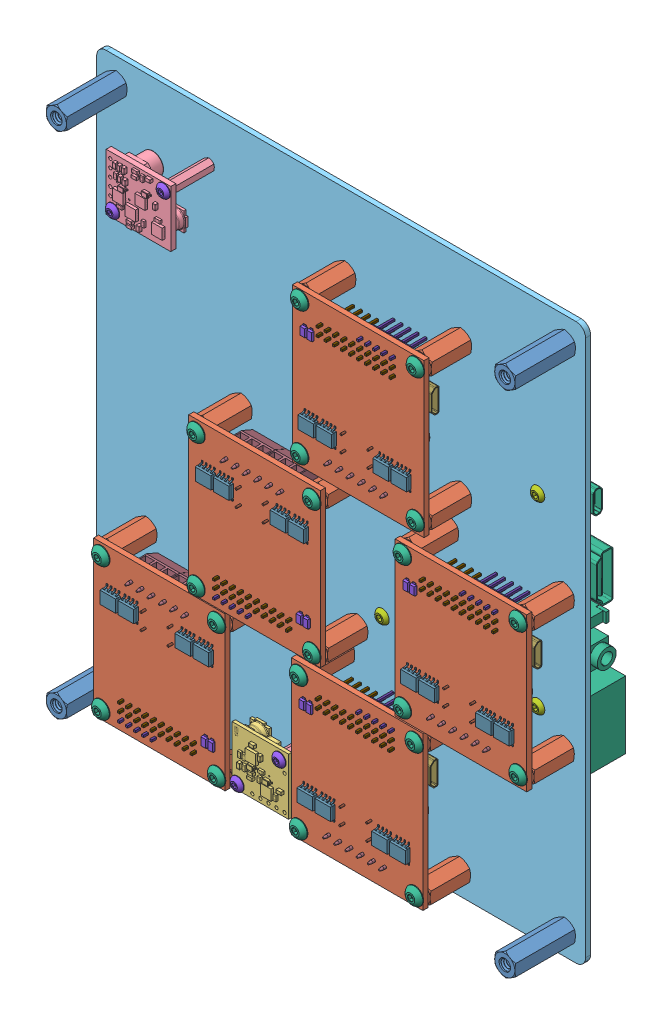
SolidWorks assembly Control Board PCB, configuration Default. Lengths in mm.
Overall size (154 175 47.64).
231 component instances, 26 part files, 69 mates.
Components (placement in the parent):
- 91780A131_ALUM FEM THRDED HEX STANDOFF-1: 91780A131_ALUM FEM THRDED HEX STANDOFF [91780A131] at (-70.612 80.137 11.125) size (6.35 7.33 20.14)
- 91780A164_ALUM FEM THRDED HEX STANDOFF-1: 91780A164_ALUM FEM THRDED HEX STANDOFF [91780A164] at (70.2626 -30.7591 7.95) size (6.35 7.33 13.57)
- 91780A164_ALUM FEM THRDED HEX STANDOFF-2: 91780A164_ALUM FEM THRDED HEX STANDOFF [91780A164] at (5.259 -30.019 7.95) size (6.35 7.33 13.57)
- 91780A164_ALUM FEM THRDED HEX STANDOFF-3: 91780A164_ALUM FEM THRDED HEX STANDOFF [91780A164] at (37.5758 -80.0977 7.95) size (6.35 7.33 13.57)
- 91780A164_ALUM FEM THRDED HEX STANDOFF-4: 91780A164_ALUM FEM THRDED HEX STANDOFF [91780A164] at (-24.7143 -78.6176 7.95) size (6.35 7.33 13.57)
- 91780A164_ALUM FEM THRDED HEX STANDOFF-5: 91780A164_ALUM FEM THRDED HEX STANDOFF [91780A164] at (37.9094 22.4005 7.95) size (6.35 7.33 13.57)
- 95947A005_ALUM FEM THRDED HEX STANDOFF-1: 95947A005_ALUM FEM THRDED HEX STANDOFF [95947A005] at (61.986 34.5817 -5) size (4.5 5.2 10.35)
- 91780A032_ALUM FEM THRDED HEX STANDOFF-1: 91780A032_ALUM FEM THRDED HEX STANDOFF [91780A032] at (-57.5189 59.1317 7.95) size (3.17 3.67 13.32)
- 91780A032_ALUM FEM THRDED HEX STANDOFF-2: 91780A032_ALUM FEM THRDED HEX STANDOFF [91780A032] at (-41.5189 72.6317 7.95) size (3.17 3.67 13.32)
- 91780A032_ALUM FEM THRDED HEX STANDOFF-3: 91780A032_ALUM FEM THRDED HEX STANDOFF [91780A032] at (-18.3018 -77.5283 7.95) size (3.17 3.67 13.32)
- 91780A032_ALUM FEM THRDED HEX STANDOFF-4: 91780A032_ALUM FEM THRDED HEX STANDOFF [91780A032] at (-5.1018 -64.3283 7.95) size (3.17 3.67 13.32)
- Control Board PCB-1: Control Board PCB [Default] at origin size (154 175 1.6)
- 91780A131_ALUM FEM THRDED HEX STANDOFF-2: 91780A131_ALUM FEM THRDED HEX STANDOFF [91780A131] at (-70.612 -80.137 11.125) size (6.35 7.33 20.14)
- 91780A131_ALUM FEM THRDED HEX STANDOFF-3: 91780A131_ALUM FEM THRDED HEX STANDOFF [91780A131] at (70.612 80.137 11.125) size (6.35 7.33 20.14)
- 91780A131_ALUM FEM THRDED HEX STANDOFF-4: 91780A131_ALUM FEM THRDED HEX STANDOFF [91780A131] at (70.612 -80.137 11.125) size (6.35 7.33 20.14)
- 91780A164_ALUM FEM THRDED HEX STANDOFF-6: 91780A164_ALUM FEM THRDED HEX STANDOFF [91780A164] at (70.2626 11.1509 7.95) size (6.35 7.33 13.57)
- 91780A164_ALUM FEM THRDED HEX STANDOFF-7: 91780A164_ALUM FEM THRDED HEX STANDOFF [91780A164] at (33.8136 -30.7591 7.95) size (6.35 7.33 13.57)
- 91780A164_ALUM FEM THRDED HEX STANDOFF-8: 91780A164_ALUM FEM THRDED HEX STANDOFF [91780A164] at (33.8136 11.1509 7.95) size (6.35 7.33 13.57)
- 91780A164_ALUM FEM THRDED HEX STANDOFF-9: 91780A164_ALUM FEM THRDED HEX STANDOFF [91780A164] at (37.9094 64.3105 7.95) size (6.35 7.33 13.57)
- 91780A164_ALUM FEM THRDED HEX STANDOFF-10: 91780A164_ALUM FEM THRDED HEX STANDOFF [91780A164] at (1.4604 22.4005 7.95) size (6.35 7.33 13.57)
- 91780A164_ALUM FEM THRDED HEX STANDOFF-11: 91780A164_ALUM FEM THRDED HEX STANDOFF [91780A164] at (1.4604 64.3105 7.95) size (6.35 7.33 13.57)
- 91780A164_ALUM FEM THRDED HEX STANDOFF-12: 91780A164_ALUM FEM THRDED HEX STANDOFF [91780A164] at (5.259 11.891 7.95) size (6.35 7.33 13.57)
- 91780A164_ALUM FEM THRDED HEX STANDOFF-13: 91780A164_ALUM FEM THRDED HEX STANDOFF [91780A164] at (-31.19 -30.019 7.95) size (6.35 7.33 13.57)
- 91780A164_ALUM FEM THRDED HEX STANDOFF-14: 91780A164_ALUM FEM THRDED HEX STANDOFF [91780A164] at (-31.19 11.891 7.95) size (6.35 7.33 13.57)
- 91780A164_ALUM FEM THRDED HEX STANDOFF-15: 91780A164_ALUM FEM THRDED HEX STANDOFF [91780A164] at (-24.7143 -36.7076 7.95) size (6.35 7.33 13.57)
- 91780A164_ALUM FEM THRDED HEX STANDOFF-16: 91780A164_ALUM FEM THRDED HEX STANDOFF [91780A164] at (-61.1633 -78.6176 7.95) size (6.35 7.33 13.57)
- 91780A164_ALUM FEM THRDED HEX STANDOFF-17: 91780A164_ALUM FEM THRDED HEX STANDOFF [91780A164] at (-61.1633 -36.7076 7.95) size (6.35 7.33 13.57)
- 91780A164_ALUM FEM THRDED HEX STANDOFF-18: 91780A164_ALUM FEM THRDED HEX STANDOFF [91780A164] at (37.5758 -38.1877 7.95) size (6.35 7.33 13.57)
- 91780A164_ALUM FEM THRDED HEX STANDOFF-19: 91780A164_ALUM FEM THRDED HEX STANDOFF [91780A164] at (1.1268 -80.0977 7.95) size (6.35 7.33 13.57)
- 91780A164_ALUM FEM THRDED HEX STANDOFF-20: 91780A164_ALUM FEM THRDED HEX STANDOFF [91780A164] at (1.1268 -38.1877 7.95) size (6.35 7.33 13.57)
- 95947A005_ALUM FEM THRDED HEX STANDOFF-2: 95947A005_ALUM FEM THRDED HEX STANDOFF [95947A005] at (61.986 -23.4183 -5) size (4.5 5.2 10.35)
- 95947A005_ALUM FEM THRDED HEX STANDOFF-3: 95947A005_ALUM FEM THRDED HEX STANDOFF [95947A005] at (12.986 34.5817 -5) size (4.5 5.2 10.35)
- 95947A005_ALUM FEM THRDED HEX STANDOFF-4: 95947A005_ALUM FEM THRDED HEX STANDOFF [95947A005] at (12.986 -23.4183 -5) size (4.5 5.2 10.35)
- RASPBERRY PI 3-1: RASPBERRY PI 3 [Default] at (37.486 -4.4183 -10) x (0 -1 0) z (1 0 0) size (87.3 17.5 58.35)
- Roboclaw-1: Roboclaw [Default] at (78.0237 51.263 53.8455) x (-1 0 0) z (0 -1 0) size (41.97 16.45 48.28)
  - 404-1004-1-ND-4: 404-1004-1-ND [Default] at (73.9119 39.5455 59.9969) size (1.6 0.7 0.8)
  - 404-1004-1-ND-5: 404-1004-1-ND [Default] at (73.9119 39.5455 61.8654) size (1.6 0.7 0.8)
  - 404-1004-1-ND-6: 404-1004-1-ND [Default] at (73.9119 39.5455 63.6743) size (1.6 0.7 0.8)
  - DB2W40200LCT-ND-3: DB2W40200LCT-ND [Default] at (76.3453 37.9455 73.6091) x (0 0 1) z (1 0 0) size (3.5 0.8 1.6)
  - DB2W40200LCT-ND-4: DB2W40200LCT-ND [Default] at (74.2192 37.9455 73.6091) x (0 0 1) z (1 0 0) size (3.5 0.8 1.6)
  - 587-3248-1-ND-3: 587-3248-1-ND [Default] at (102.2216 40.4955 58.909) x (0 0 -1) z (1 0 0) size (1.6 1.9 3.2)
  - 587-3248-1-ND-4: 587-3248-1-ND [Default] at (107.6317 40.4955 65.3191) x (0 0 -1) z (1 0 0) size (1.6 1.9 3.2)
  - SRN5040-220MCT-ND-2: SRN5040-220MCT-ND [Default] at (105.6664 42.9455 62.8284) x (-1 0 0) z (0 0 1) size (2.21 2 2.21)
  - P15369TB-ND-3: P15369TB-ND [Default] at (95.395 39.5455 49.7941) x (-1 0 0) z (0 0 -1) size (8 16 8)
  - 609-4618-1-ND-2: 609-4618-1-ND [Default] at (112.2359 40.9455 71.8547) x (0 0 -1) z (1 0 0) size (7.5 3.05 5)
  - ED2636-ND-3: ED2636-ND [Default] at (85.709 39.5455 41.8431) x (-1 0 0) z (0 0 -1) size (10.5 11.85 7)
  - IRF7351TRPBFCT-ND-5: IRF7351TRPBFCT-ND [Default] at (76.1828 37.6966 49.2664) x (-1 0 0) z (0 0 1) size (5 1.75 6.2)
  - IRF7351TRPBFCT-ND-6: IRF7351TRPBFCT-ND [Default] at (81.9001 37.6966 49.2664) x (-1 0 0) z (0 0 1) size (5 1.75 6.2)
  - IRF7351TRPBFCT-ND-7: IRF7351TRPBFCT-ND [Default] at (99.7733 37.6966 49.2664) x (-1 0 0) z (0 0 1) size (5 1.75 6.2)
  - IRF7351TRPBFCT-ND-8: IRF7351TRPBFCT-ND [Default] at (105.4543 37.6966 49.2664) x (-1 0 0) z (0 0 1) size (5 1.75 6.2)
  - 620-1319-1-ND-3: 620-1319-1-ND [Default] at (106.2731 39.6955 50.308) size (7.8 1.2 6.4)
  - 620-1319-1-ND-4: 620-1319-1-ND [Default] at (77.2465 39.6955 50.308) size (7.8 1.2 6.4)
  - ATXMEGA32A4U-AU-ND-2: ATXMEGA32A4U-AU-ND [Default] at (87.74 39.7455 63.8454) x (0 0 -1) z (1 0 0) size (12 1.2 12)
  - PBC05SAAN-2: PBC05SAAN [Default] at (92.2279 39.5455 80.6492) size (12.7 11.43 2.54)
  - PBC10DAAN-2: PBC10DAAN [Default] at (79.5294 39.5455 76.739) size (25.4 11.43 5.08)
  - SW1020CT-ND-4: SW1020CT-ND [Default] at (73.2925 39.5455 66.2406) x (-1 0 0) z (0 0 -1) size (4 1.6 2.5)
  - SW1020CT-ND-5: SW1020CT-ND [Default] at (73.2925 39.5455 70.7286) x (-1 0 0) z (0 0 -1) size (4 1.6 2.5)
  - SW1020CT-ND-6: SW1020CT-ND [Default] at (73.2925 39.5455 75.1362) x (-1 0 0) z (0 0 -1) size (4 1.6 2.5)
  - P15369TB-ND-4: P15369TB-ND [Default] at (86.9008 39.5455 49.7923) x (-1 0 0) z (0 0 -1) size (8 16 8)
  - ED2636-ND-4: ED2636-ND [Default] at (96.2918 39.5455 41.8431) x (-1 0 0) z (0 0 -1) size (10.5 11.85 7)
  - MC5A-PCB-2: MC5A-PCB [Default] at (90.9892 37.9455 60.0095) size (41.44 1.6 48.28)
- Roboclaw-2: Roboclaw [Default] at (48.0505 2.6645 53.8455) x (-1 0 0) z (0 -1 0) size (41.97 16.45 48.28)
  - 404-1004-1-ND-4: 404-1004-1-ND [Default] at (73.9119 39.5455 59.9969) size (1.6 0.7 0.8)
  - 404-1004-1-ND-5: 404-1004-1-ND [Default] at (73.9119 39.5455 61.8654) size (1.6 0.7 0.8)
  - 404-1004-1-ND-6: 404-1004-1-ND [Default] at (73.9119 39.5455 63.6743) size (1.6 0.7 0.8)
  - DB2W40200LCT-ND-3: DB2W40200LCT-ND [Default] at (76.3453 37.9455 73.6091) x (0 0 1) z (1 0 0) size (3.5 0.8 1.6)
  - DB2W40200LCT-ND-4: DB2W40200LCT-ND [Default] at (74.2192 37.9455 73.6091) x (0 0 1) z (1 0 0) size (3.5 0.8 1.6)
  - 587-3248-1-ND-3: 587-3248-1-ND [Default] at (102.2216 40.4955 58.909) x (0 0 -1) z (1 0 0) size (1.6 1.9 3.2)
  - 587-3248-1-ND-4: 587-3248-1-ND [Default] at (107.6317 40.4955 65.3191) x (0 0 -1) z (1 0 0) size (1.6 1.9 3.2)
  - SRN5040-220MCT-ND-2: SRN5040-220MCT-ND [Default] at (105.6664 42.9455 62.8284) x (-1 0 0) z (0 0 1) size (2.21 2 2.21)
  - P15369TB-ND-3: P15369TB-ND [Default] at (95.395 39.5455 49.7941) x (-1 0 0) z (0 0 -1) size (8 16 8)
  - 609-4618-1-ND-2: 609-4618-1-ND [Default] at (112.2359 40.9455 71.8547) x (0 0 -1) z (1 0 0) size (7.5 3.05 5)
  - ED2636-ND-3: ED2636-ND [Default] at (85.709 39.5455 41.8431) x (-1 0 0) z (0 0 -1) size (10.5 11.85 7)
  - IRF7351TRPBFCT-ND-5: IRF7351TRPBFCT-ND [Default] at (76.1828 37.6966 49.2664) x (-1 0 0) z (0 0 1) size (5 1.75 6.2)
  - IRF7351TRPBFCT-ND-6: IRF7351TRPBFCT-ND [Default] at (81.9001 37.6966 49.2664) x (-1 0 0) z (0 0 1) size (5 1.75 6.2)
  - IRF7351TRPBFCT-ND-7: IRF7351TRPBFCT-ND [Default] at (99.7733 37.6966 49.2664) x (-1 0 0) z (0 0 1) size (5 1.75 6.2)
  - IRF7351TRPBFCT-ND-8: IRF7351TRPBFCT-ND [Default] at (105.4543 37.6966 49.2664) x (-1 0 0) z (0 0 1) size (5 1.75 6.2)
  - 620-1319-1-ND-3: 620-1319-1-ND [Default] at (106.2731 39.6955 50.308) size (7.8 1.2 6.4)
  - 620-1319-1-ND-4: 620-1319-1-ND [Default] at (77.2465 39.6955 50.308) size (7.8 1.2 6.4)
  - ATXMEGA32A4U-AU-ND-2: ATXMEGA32A4U-AU-ND [Default] at (87.74 39.7455 63.8454) x (0 0 -1) z (1 0 0) size (12 1.2 12)
  - PBC05SAAN-2: PBC05SAAN [Default] at (92.2279 39.5455 80.6492) size (12.7 11.43 2.54)
  - PBC10DAAN-2: PBC10DAAN [Default] at (79.5294 39.5455 76.739) size (25.4 11.43 5.08)
  - SW1020CT-ND-4: SW1020CT-ND [Default] at (73.2925 39.5455 66.2406) x (-1 0 0) z (0 0 -1) size (4 1.6 2.5)
  - SW1020CT-ND-5: SW1020CT-ND [Default] at (73.2925 39.5455 70.7286) x (-1 0 0) z (0 0 -1) size (4 1.6 2.5)
  - SW1020CT-ND-6: SW1020CT-ND [Default] at (73.2925 39.5455 75.1362) x (-1 0 0) z (0 0 -1) size (4 1.6 2.5)
  - P15369TB-ND-4: P15369TB-ND [Default] at (86.9008 39.5455 49.7923) x (-1 0 0) z (0 0 -1) size (8 16 8)
  - ED2636-ND-4: ED2636-ND [Default] at (96.2918 39.5455 41.8431) x (-1 0 0) z (0 0 -1) size (10.5 11.85 7)
  - MC5A-PCB-2: MC5A-PCB [Default] at (90.9892 37.9455 60.0095) size (41.44 1.6 48.28)
- Roboclaw-3: Roboclaw [Default] at (-38.9511 -70.1311 53.8455) x (1 0 0) z (0 1 0) size (41.97 16.45 48.28)
  - 404-1004-1-ND-4: 404-1004-1-ND [Default] at (73.9119 39.5455 59.9969) size (1.6 0.7 0.8)
  - 404-1004-1-ND-5: 404-1004-1-ND [Default] at (73.9119 39.5455 61.8654) size (1.6 0.7 0.8)
  - 404-1004-1-ND-6: 404-1004-1-ND [Default] at (73.9119 39.5455 63.6743) size (1.6 0.7 0.8)
  - DB2W40200LCT-ND-3: DB2W40200LCT-ND [Default] at (76.3453 37.9455 73.6091) x (0 0 1) z (1 0 0) size (3.5 0.8 1.6)
  - DB2W40200LCT-ND-4: DB2W40200LCT-ND [Default] at (74.2192 37.9455 73.6091) x (0 0 1) z (1 0 0) size (3.5 0.8 1.6)
  - 587-3248-1-ND-3: 587-3248-1-ND [Default] at (102.2216 40.4955 58.909) x (0 0 -1) z (1 0 0) size (1.6 1.9 3.2)
  - 587-3248-1-ND-4: 587-3248-1-ND [Default] at (107.6317 40.4955 65.3191) x (0 0 -1) z (1 0 0) size (1.6 1.9 3.2)
  - SRN5040-220MCT-ND-2: SRN5040-220MCT-ND [Default] at (105.6664 42.9455 62.8284) x (-1 0 0) z (0 0 1) size (2.21 2 2.21)
  - P15369TB-ND-3: P15369TB-ND [Default] at (95.395 39.5455 49.7941) x (-1 0 0) z (0 0 -1) size (8 16 8)
  - 609-4618-1-ND-2: 609-4618-1-ND [Default] at (112.2359 40.9455 71.8547) x (0 0 -1) z (1 0 0) size (7.5 3.05 5)
  - ED2636-ND-3: ED2636-ND [Default] at (85.709 39.5455 41.8431) x (-1 0 0) z (0 0 -1) size (10.5 11.85 7)
  - IRF7351TRPBFCT-ND-5: IRF7351TRPBFCT-ND [Default] at (76.1828 37.6966 49.2664) x (-1 0 0) z (0 0 1) size (5 1.75 6.2)
  - IRF7351TRPBFCT-ND-6: IRF7351TRPBFCT-ND [Default] at (81.9001 37.6966 49.2664) x (-1 0 0) z (0 0 1) size (5 1.75 6.2)
  - IRF7351TRPBFCT-ND-7: IRF7351TRPBFCT-ND [Default] at (99.7733 37.6966 49.2664) x (-1 0 0) z (0 0 1) size (5 1.75 6.2)
  - IRF7351TRPBFCT-ND-8: IRF7351TRPBFCT-ND [Default] at (105.4543 37.6966 49.2664) x (-1 0 0) z (0 0 1) size (5 1.75 6.2)
  - 620-1319-1-ND-3: 620-1319-1-ND [Default] at (106.2731 39.6955 50.308) size (7.8 1.2 6.4)
  - 620-1319-1-ND-4: 620-1319-1-ND [Default] at (77.2465 39.6955 50.308) size (7.8 1.2 6.4)
  - ATXMEGA32A4U-AU-ND-2: ATXMEGA32A4U-AU-ND [Default] at (87.74 39.7455 63.8454) x (0 0 -1) z (1 0 0) size (12 1.2 12)
  - PBC05SAAN-2: PBC05SAAN [Default] at (92.2279 39.5455 80.6492) size (12.7 11.43 2.54)
  - PBC10DAAN-2: PBC10DAAN [Default] at (79.5294 39.5455 76.739) size (25.4 11.43 5.08)
  - SW1020CT-ND-4: SW1020CT-ND [Default] at (73.2925 39.5455 66.2406) x (-1 0 0) z (0 0 -1) size (4 1.6 2.5)
  - SW1020CT-ND-5: SW1020CT-ND [Default] at (73.2925 39.5455 70.7286) x (-1 0 0) z (0 0 -1) size (4 1.6 2.5)
  - SW1020CT-ND-6: SW1020CT-ND [Default] at (73.2925 39.5455 75.1362) x (-1 0 0) z (0 0 -1) size (4 1.6 2.5)
  - P15369TB-ND-4: P15369TB-ND [Default] at (86.9008 39.5455 49.7923) x (-1 0 0) z (0 0 -1) size (8 16 8)
  - ED2636-ND-4: ED2636-ND [Default] at (96.2918 39.5455 41.8431) x (-1 0 0) z (0 0 -1) size (10.5 11.85 7)
  - MC5A-PCB-2: MC5A-PCB [Default] at (90.9892 37.9455 60.0095) size (41.44 1.6 48.28)
- Roboclaw-4: Roboclaw [Default] at (-71.3044 -16.9716 53.8455) x (1 0 0) z (0 1 0) size (41.97 16.45 48.28)
  - 404-1004-1-ND-4: 404-1004-1-ND [Default] at (73.9119 39.5455 59.9969) size (1.6 0.7 0.8)
  - 404-1004-1-ND-5: 404-1004-1-ND [Default] at (73.9119 39.5455 61.8654) size (1.6 0.7 0.8)
  - 404-1004-1-ND-6: 404-1004-1-ND [Default] at (73.9119 39.5455 63.6743) size (1.6 0.7 0.8)
  - DB2W40200LCT-ND-3: DB2W40200LCT-ND [Default] at (76.3453 37.9455 73.6091) x (0 0 1) z (1 0 0) size (3.5 0.8 1.6)
  - DB2W40200LCT-ND-4: DB2W40200LCT-ND [Default] at (74.2192 37.9455 73.6091) x (0 0 1) z (1 0 0) size (3.5 0.8 1.6)
  - 587-3248-1-ND-3: 587-3248-1-ND [Default] at (102.2216 40.4955 58.909) x (0 0 -1) z (1 0 0) size (1.6 1.9 3.2)
  - 587-3248-1-ND-4: 587-3248-1-ND [Default] at (107.6317 40.4955 65.3191) x (0 0 -1) z (1 0 0) size (1.6 1.9 3.2)
  - SRN5040-220MCT-ND-2: SRN5040-220MCT-ND [Default] at (105.6664 42.9455 62.8284) x (-1 0 0) z (0 0 1) size (2.21 2 2.21)
  - P15369TB-ND-3: P15369TB-ND [Default] at (95.395 39.5455 49.7941) x (-1 0 0) z (0 0 -1) size (8 16 8)
  - 609-4618-1-ND-2: 609-4618-1-ND [Default] at (112.2359 40.9455 71.8547) x (0 0 -1) z (1 0 0) size (7.5 3.05 5)
  - ED2636-ND-3: ED2636-ND [Default] at (85.709 39.5455 41.8431) x (-1 0 0) z (0 0 -1) size (10.5 11.85 7)
  - IRF7351TRPBFCT-ND-5: IRF7351TRPBFCT-ND [Default] at (76.1828 37.6966 49.2664) x (-1 0 0) z (0 0 1) size (5 1.75 6.2)
  - IRF7351TRPBFCT-ND-6: IRF7351TRPBFCT-ND [Default] at (81.9001 37.6966 49.2664) x (-1 0 0) z (0 0 1) size (5 1.75 6.2)
  - IRF7351TRPBFCT-ND-7: IRF7351TRPBFCT-ND [Default] at (99.7733 37.6966 49.2664) x (-1 0 0) z (0 0 1) size (5 1.75 6.2)
  - IRF7351TRPBFCT-ND-8: IRF7351TRPBFCT-ND [Default] at (105.4543 37.6966 49.2664) x (-1 0 0) z (0 0 1) size (5 1.75 6.2)
  - 620-1319-1-ND-3: 620-1319-1-ND [Default] at (106.2731 39.6955 50.308) size (7.8 1.2 6.4)
  - 620-1319-1-ND-4: 620-1319-1-ND [Default] at (77.2465 39.6955 50.308) size (7.8 1.2 6.4)
  - ATXMEGA32A4U-AU-ND-2: ATXMEGA32A4U-AU-ND [Default] at (87.74 39.7455 63.8454) x (0 0 -1) z (1 0 0) size (12 1.2 12)
  - PBC05SAAN-2: PBC05SAAN [Default] at (92.2279 39.5455 80.6492) size (12.7 11.43 2.54)
  - PBC10DAAN-2: PBC10DAAN [Default] at (79.5294 39.5455 76.739) size (25.4 11.43 5.08)
  - SW1020CT-ND-4: SW1020CT-ND [Default] at (73.2925 39.5455 66.2406) x (-1 0 0) z (0 0 -1) size (4 1.6 2.5)
  - SW1020CT-ND-5: SW1020CT-ND [Default] at (73.2925 39.5455 70.7286) x (-1 0 0) z (0 0 -1) size (4 1.6 2.5)
  - SW1020CT-ND-6: SW1020CT-ND [Default] at (73.2925 39.5455 75.1362) x (-1 0 0) z (0 0 -1) size (4 1.6 2.5)
  - P15369TB-ND-4: P15369TB-ND [Default] at (86.9008 39.5455 49.7923) x (-1 0 0) z (0 0 -1) size (8 16 8)
  - ED2636-ND-4: ED2636-ND [Default] at (96.2918 39.5455 41.8431) x (-1 0 0) z (0 0 -1) size (10.5 11.85 7)
  - MC5A-PCB-2: MC5A-PCB [Default] at (90.9892 37.9455 60.0095) size (41.44 1.6 48.28)
- Roboclaw-5: Roboclaw [Default] at (-71.638 -118.8347 53.8455) x (1 0 0) z (0 1 0) size (41.97 16.45 48.28)
  - 404-1004-1-ND-4: 404-1004-1-ND [Default] at (73.9119 39.5455 59.9969) size (1.6 0.7 0.8)
  - 404-1004-1-ND-5: 404-1004-1-ND [Default] at (73.9119 39.5455 61.8654) size (1.6 0.7 0.8)
  - 404-1004-1-ND-6: 404-1004-1-ND [Default] at (73.9119 39.5455 63.6743) size (1.6 0.7 0.8)
  - DB2W40200LCT-ND-3: DB2W40200LCT-ND [Default] at (76.3453 37.9455 73.6091) x (0 0 1) z (1 0 0) size (3.5 0.8 1.6)
  - DB2W40200LCT-ND-4: DB2W40200LCT-ND [Default] at (74.2192 37.9455 73.6091) x (0 0 1) z (1 0 0) size (3.5 0.8 1.6)
  - 587-3248-1-ND-3: 587-3248-1-ND [Default] at (102.2216 40.4955 58.909) x (0 0 -1) z (1 0 0) size (1.6 1.9 3.2)
  - 587-3248-1-ND-4: 587-3248-1-ND [Default] at (107.6317 40.4955 65.3191) x (0 0 -1) z (1 0 0) size (1.6 1.9 3.2)
  - SRN5040-220MCT-ND-2: SRN5040-220MCT-ND [Default] at (105.6664 42.9455 62.8284) x (-1 0 0) z (0 0 1) size (2.21 2 2.21)
  - P15369TB-ND-3: P15369TB-ND [Default] at (95.395 39.5455 49.7941) x (-1 0 0) z (0 0 -1) size (8 16 8)
  - 609-4618-1-ND-2: 609-4618-1-ND [Default] at (112.2359 40.9455 71.8547) x (0 0 -1) z (1 0 0) size (7.5 3.05 5)
  - ED2636-ND-3: ED2636-ND [Default] at (85.709 39.5455 41.8431) x (-1 0 0) z (0 0 -1) size (10.5 11.85 7)
  - IRF7351TRPBFCT-ND-5: IRF7351TRPBFCT-ND [Default] at (76.1828 37.6966 49.2664) x (-1 0 0) z (0 0 1) size (5 1.75 6.2)
  - IRF7351TRPBFCT-ND-6: IRF7351TRPBFCT-ND [Default] at (81.9001 37.6966 49.2664) x (-1 0 0) z (0 0 1) size (5 1.75 6.2)
  - IRF7351TRPBFCT-ND-7: IRF7351TRPBFCT-ND [Default] at (99.7733 37.6966 49.2664) x (-1 0 0) z (0 0 1) size (5 1.75 6.2)
  - IRF7351TRPBFCT-ND-8: IRF7351TRPBFCT-ND [Default] at (105.4543 37.6966 49.2664) x (-1 0 0) z (0 0 1) size (5 1.75 6.2)
  - 620-1319-1-ND-3: 620-1319-1-ND [Default] at (106.2731 39.6955 50.308) size (7.8 1.2 6.4)
  - 620-1319-1-ND-4: 620-1319-1-ND [Default] at (77.2465 39.6955 50.308) size (7.8 1.2 6.4)
  - ATXMEGA32A4U-AU-ND-2: ATXMEGA32A4U-AU-ND [Default] at (87.74 39.7455 63.8454) x (0 0 -1) z (1 0 0) size (12 1.2 12)
  - PBC05SAAN-2: PBC05SAAN [Default] at (92.2279 39.5455 80.6492) size (12.7 11.43 2.54)
  - PBC10DAAN-2: PBC10DAAN [Default] at (79.5294 39.5455 76.739) size (25.4 11.43 5.08)
  - SW1020CT-ND-4: SW1020CT-ND [Default] at (73.2925 39.5455 66.2406) x (-1 0 0) z (0 0 -1) size (4 1.6 2.5)
  - SW1020CT-ND-5: SW1020CT-ND [Default] at (73.2925 39.5455 70.7286) x (-1 0 0) z (0 0 -1) size (4 1.6 2.5)
  - SW1020CT-ND-6: SW1020CT-ND [Default] at (73.2925 39.5455 75.1362) x (-1 0 0) z (0 0 -1) size (4 1.6 2.5)
  - P15369TB-ND-4: P15369TB-ND [Default] at (86.9008 39.5455 49.7923) x (-1 0 0) z (0 0 -1) size (8 16 8)
  - ED2636-ND-4: ED2636-ND [Default] at (96.2918 39.5455 41.8431) x (-1 0 0) z (0 0 -1) size (10.5 11.85 7)
  - MC5A-PCB-2: MC5A-PCB [Default] at (90.9892 37.9455 60.0095) size (41.44 1.6 48.28)
- d24v22fx-step-down-voltage-regulator-1: d24v22fx-step-down-voltage-regulator [Default] at (-2.8158 -79.8223 15.316) x (-1 0 0) z (0 0 -1) size (17.78 17.78 8.22)
- d24v50f5-step-down-voltage-regulator-1: d24v50f5-step-down-voltage-regulator [Default] at (-59.6799 57.0107 15.8748) x (0 1 0) z (0 0 -1) size (17.78 20.32 8.78)
- 92949A146_18-8 SS BUTTON-HEAD SOCKET CAP SCREW-1: 92949A146_18-8 SS BUTTON-HEAD SOCKET CAP SCREW [92949A146] at (-70.612 80.137 -1.8542) x (-0.923728 -0.383049 0) z (0 0 -1) size (6.65 6.65 11.77)
- 92949A106_18-8 SS BUTTON-HEAD SOCKET CAP SCREW-1: 92949A106_18-8 SS BUTTON-HEAD SOCKET CAP SCREW [92949A106] at (70.2626 -30.7591 -1.4986) x (-0.923728 -0.383049 0) z (0 0 -1) size (5.41 5.41 8.16)
- 92949A106_18-8 SS BUTTON-HEAD SOCKET CAP SCREW-2: 92949A106_18-8 SS BUTTON-HEAD SOCKET CAP SCREW [92949A106] at (-24.7143 -78.6176 -1.4986) x (-0.923728 -0.383049 0) z (0 0 -1) size (5.41 5.41 8.16)
- 92949A106_18-8 SS BUTTON-HEAD SOCKET CAP SCREW-3: 92949A106_18-8 SS BUTTON-HEAD SOCKET CAP SCREW [92949A106] at (5.259 -30.019 -1.4986) x (0.923728 0.383049 0) z (0 0 -1) size (5.41 5.41 8.16)
- 92949A106_18-8 SS BUTTON-HEAD SOCKET CAP SCREW-4: 92949A106_18-8 SS BUTTON-HEAD SOCKET CAP SCREW [92949A106] at (37.9094 22.4005 -1.4986) x (-0.923728 -0.383049 0) z (0 0 -1) size (5.41 5.41 8.16)
- 92949A106_18-8 SS BUTTON-HEAD SOCKET CAP SCREW-5: 92949A106_18-8 SS BUTTON-HEAD SOCKET CAP SCREW [92949A106] at (37.5758 -80.0977 -1.4986) x (-0.923728 -0.383049 0) z (0 0 -1) size (5.41 5.41 8.16)
- 92095A458_18-8 SS BUTTON-HEAD SOCKET CAP SCREW-1: 92095A458_18-8 SS BUTTON-HEAD SOCKET CAP SCREW [92095A458] at (61.986 34.5817 -12.65) x (-0.923728 -0.383049 0) z (0 0 -1) size (4.5 4.5 7.75)
- 91255A077_ALLOY STEEL BUTTON-HEAD SOCKET CAP SCREW-1: 91255A077_ALLOY STEEL BUTTON-HEAD SOCKET CAP SCREW [91255A077] at (-41.5189 72.6317 -1.1684) x (0.923728 0.383049 0) z (0 0 -1) size (4.17 4.17 7.76)
- 91255A077_ALLOY STEEL BUTTON-HEAD SOCKET CAP SCREW-2: 91255A077_ALLOY STEEL BUTTON-HEAD SOCKET CAP SCREW [91255A077] at (-57.5189 59.1317 -1.1684) x (-0.923728 -0.383049 0) z (0 0 -1) size (4.17 4.17 7.76)
- 91255A077_ALLOY STEEL BUTTON-HEAD SOCKET CAP SCREW-3: 91255A077_ALLOY STEEL BUTTON-HEAD SOCKET CAP SCREW [91255A077] at (-5.1018 -64.3283 -1.1684) x (0.923728 0.383049 0) z (0 0 -1) size (4.17 4.17 7.76)
- 91255A077_ALLOY STEEL BUTTON-HEAD SOCKET CAP SCREW-4: 91255A077_ALLOY STEEL BUTTON-HEAD SOCKET CAP SCREW [91255A077] at (-18.3018 -77.5283 -1.1684) x (0.923728 0.383049 0) z (0 0 -1) size (4.17 4.17 7.76)
- 92949A146_18-8 SS BUTTON-HEAD SOCKET CAP SCREW-2: 92949A146_18-8 SS BUTTON-HEAD SOCKET CAP SCREW [92949A146] at (-70.612 -80.137 -1.8542) x (-0.923728 -0.383049 0) z (0 0 -1) size (6.65 6.65 11.77)
- 92949A146_18-8 SS BUTTON-HEAD SOCKET CAP SCREW-3: 92949A146_18-8 SS BUTTON-HEAD SOCKET CAP SCREW [92949A146] at (70.612 80.137 -1.8542) x (-0.923728 -0.383049 0) z (0 0 -1) size (6.65 6.65 11.77)
- 92949A146_18-8 SS BUTTON-HEAD SOCKET CAP SCREW-4: 92949A146_18-8 SS BUTTON-HEAD SOCKET CAP SCREW [92949A146] at (70.612 -80.137 -1.8542) x (-0.923728 -0.383049 0) z (0 0 -1) size (6.65 6.65 11.77)
- 92949A106_18-8 SS BUTTON-HEAD SOCKET CAP SCREW-6: 92949A106_18-8 SS BUTTON-HEAD SOCKET CAP SCREW [92949A106] at (37.9094 64.3105 -1.4986) x (-0.923728 -0.383049 0) z (0 0 -1) size (5.41 5.41 8.16)
- 92949A106_18-8 SS BUTTON-HEAD SOCKET CAP SCREW-7: 92949A106_18-8 SS BUTTON-HEAD SOCKET CAP SCREW [92949A106] at (1.4604 22.4005 -1.4986) x (-0.923728 -0.383049 0) z (0 0 -1) size (5.41 5.41 8.16)
- 92949A106_18-8 SS BUTTON-HEAD SOCKET CAP SCREW-8: 92949A106_18-8 SS BUTTON-HEAD SOCKET CAP SCREW [92949A106] at (1.4604 64.3105 -1.4986) x (-0.923728 -0.383049 0) z (0 0 -1) size (5.41 5.41 8.16)
- 92949A106_18-8 SS BUTTON-HEAD SOCKET CAP SCREW-9: 92949A106_18-8 SS BUTTON-HEAD SOCKET CAP SCREW [92949A106] at (5.259 11.891 -1.4986) x (0.923728 0.383049 0) z (0 0 -1) size (5.41 5.41 8.16)
- 92949A106_18-8 SS BUTTON-HEAD SOCKET CAP SCREW-10: 92949A106_18-8 SS BUTTON-HEAD SOCKET CAP SCREW [92949A106] at (-31.19 -30.019 -1.4986) x (0.923728 0.383049 0) z (0 0 -1) size (5.41 5.41 8.16)
- 92949A106_18-8 SS BUTTON-HEAD SOCKET CAP SCREW-11: 92949A106_18-8 SS BUTTON-HEAD SOCKET CAP SCREW [92949A106] at (-31.19 11.891 -1.4986) x (0.923728 0.383049 0) z (0 0 -1) size (5.41 5.41 8.16)
- 92949A106_18-8 SS BUTTON-HEAD SOCKET CAP SCREW-12: 92949A106_18-8 SS BUTTON-HEAD SOCKET CAP SCREW [92949A106] at (-24.7143 -36.7076 -1.4986) x (-0.923728 -0.383049 0) z (0 0 -1) size (5.41 5.41 8.16)
- 92949A106_18-8 SS BUTTON-HEAD SOCKET CAP SCREW-13: 92949A106_18-8 SS BUTTON-HEAD SOCKET CAP SCREW [92949A106] at (-61.1633 -78.6176 -1.4986) x (-0.923728 -0.383049 0) z (0 0 -1) size (5.41 5.41 8.16)
- 92949A106_18-8 SS BUTTON-HEAD SOCKET CAP SCREW-14: 92949A106_18-8 SS BUTTON-HEAD SOCKET CAP SCREW [92949A106] at (-61.1633 -36.7076 -1.4986) x (-0.923728 -0.383049 0) z (0 0 -1) size (5.41 5.41 8.16)
- 92949A106_18-8 SS BUTTON-HEAD SOCKET CAP SCREW-15: 92949A106_18-8 SS BUTTON-HEAD SOCKET CAP SCREW [92949A106] at (37.5758 -38.1877 -1.4986) x (-0.923728 -0.383049 0) z (0 0 -1) size (5.41 5.41 8.16)
- 92949A106_18-8 SS BUTTON-HEAD SOCKET CAP SCREW-16: 92949A106_18-8 SS BUTTON-HEAD SOCKET CAP SCREW [92949A106] at (1.1268 -80.0977 -1.4986) x (-0.923728 -0.383049 0) z (0 0 -1) size (5.41 5.41 8.16)
- 92949A106_18-8 SS BUTTON-HEAD SOCKET CAP SCREW-17: 92949A106_18-8 SS BUTTON-HEAD SOCKET CAP SCREW [92949A106] at (1.1268 -38.1877 -1.4986) x (-0.923728 -0.383049 0) z (0 0 -1) size (5.41 5.41 8.16)
- 92949A106_18-8 SS BUTTON-HEAD SOCKET CAP SCREW-18: 92949A106_18-8 SS BUTTON-HEAD SOCKET CAP SCREW [92949A106] at (70.2626 11.1509 -1.4986) x (-0.923728 -0.383049 0) z (0 0 -1) size (5.41 5.41 8.16)
- 92949A106_18-8 SS BUTTON-HEAD SOCKET CAP SCREW-19: 92949A106_18-8 SS BUTTON-HEAD SOCKET CAP SCREW [92949A106] at (33.8136 -30.7591 -1.4986) x (-0.923728 -0.383049 0) z (0 0 -1) size (5.41 5.41 8.16)
- 92949A106_18-8 SS BUTTON-HEAD SOCKET CAP SCREW-20: 92949A106_18-8 SS BUTTON-HEAD SOCKET CAP SCREW [92949A106] at (33.8136 11.1509 -1.4986) x (-0.923728 -0.383049 0) z (0 0 -1) size (5.41 5.41 8.16)
- 92095A458_18-8 SS BUTTON-HEAD SOCKET CAP SCREW-3: 92095A458_18-8 SS BUTTON-HEAD SOCKET CAP SCREW [92095A458] at (61.986 -23.4183 -12.65) x (-0.923728 -0.383049 0) z (0 0 -1) size (4.5 4.5 7.75)
- 92095A458_18-8 SS BUTTON-HEAD SOCKET CAP SCREW-4: 92095A458_18-8 SS BUTTON-HEAD SOCKET CAP SCREW [92095A458] at (12.986 34.5817 -12.65) x (-0.923728 -0.383049 0) z (0 0 -1) size (4.5 4.5 7.75)
- 92095A458_18-8 SS BUTTON-HEAD SOCKET CAP SCREW-5: 92095A458_18-8 SS BUTTON-HEAD SOCKET CAP SCREW [92095A458] at (12.986 -23.4183 -12.65) x (-0.923728 -0.383049 0) z (0 0 -1) size (4.5 4.5 7.75)
- 92949A106_18-8 SS BUTTON-HEAD SOCKET CAP SCREW-21: 92949A106_18-8 SS BUTTON-HEAD SOCKET CAP SCREW [92949A106] at (37.9094 64.3105 17.3986) x (0.923728 0.383049 0) z (0 0 1) size (5.41 5.41 8.16)
- 92949A106_18-8 SS BUTTON-HEAD SOCKET CAP SCREW-22: 92949A106_18-8 SS BUTTON-HEAD SOCKET CAP SCREW [92949A106] at (1.4604 22.4005 17.3986) x (0.923728 0.383049 0) z (0 0 1) size (5.41 5.41 8.16)
- 92949A106_18-8 SS BUTTON-HEAD SOCKET CAP SCREW-23: 92949A106_18-8 SS BUTTON-HEAD SOCKET CAP SCREW [92949A106] at (1.4604 64.3105 17.3986) x (0.923728 0.383049 0) z (0 0 1) size (5.41 5.41 8.16)
- 92949A106_18-8 SS BUTTON-HEAD SOCKET CAP SCREW-24: 92949A106_18-8 SS BUTTON-HEAD SOCKET CAP SCREW [92949A106] at (5.259 11.891 17.3986) x (-0.923728 -0.383049 0) z (0 0 1) size (5.41 5.41 8.16)
- 92949A106_18-8 SS BUTTON-HEAD SOCKET CAP SCREW-25: 92949A106_18-8 SS BUTTON-HEAD SOCKET CAP SCREW [92949A106] at (-31.19 -30.019 17.3986) x (-0.923728 -0.383049 0) z (0 0 1) size (5.41 5.41 8.16)
- 92949A106_18-8 SS BUTTON-HEAD SOCKET CAP SCREW-26: 92949A106_18-8 SS BUTTON-HEAD SOCKET CAP SCREW [92949A106] at (-31.19 11.891 17.3986) x (-0.923728 -0.383049 0) z (0 0 1) size (5.41 5.41 8.16)
- 92949A106_18-8 SS BUTTON-HEAD SOCKET CAP SCREW-27: 92949A106_18-8 SS BUTTON-HEAD SOCKET CAP SCREW [92949A106] at (-24.7143 -36.7076 17.3986) x (0.923728 0.383049 0) z (0 0 1) size (5.41 5.41 8.16)
- 92949A106_18-8 SS BUTTON-HEAD SOCKET CAP SCREW-28: 92949A106_18-8 SS BUTTON-HEAD SOCKET CAP SCREW [92949A106] at (-61.1633 -78.6176 17.3986) x (0.923728 0.383049 0) z (0 0 1) size (5.41 5.41 8.16)
- 92949A106_18-8 SS BUTTON-HEAD SOCKET CAP SCREW-29: 92949A106_18-8 SS BUTTON-HEAD SOCKET CAP SCREW [92949A106] at (-61.1633 -36.7076 17.3986) x (0.923728 0.383049 0) z (0 0 1) size (5.41 5.41 8.16)
- 92949A106_18-8 SS BUTTON-HEAD SOCKET CAP SCREW-30: 92949A106_18-8 SS BUTTON-HEAD SOCKET CAP SCREW [92949A106] at (37.5758 -38.1877 17.3986) x (0.923728 0.383049 0) z (0 0 1) size (5.41 5.41 8.16)
- 92949A106_18-8 SS BUTTON-HEAD SOCKET CAP SCREW-31: 92949A106_18-8 SS BUTTON-HEAD SOCKET CAP SCREW [92949A106] at (1.1268 -80.0977 17.3986) x (0.923728 0.383049 0) z (0 0 1) size (5.41 5.41 8.16)
- 92949A106_18-8 SS BUTTON-HEAD SOCKET CAP SCREW-32: 92949A106_18-8 SS BUTTON-HEAD SOCKET CAP SCREW [92949A106] at (1.1268 -38.1877 17.3986) x (0.923728 0.383049 0) z (0 0 1) size (5.41 5.41 8.16)
- 92949A106_18-8 SS BUTTON-HEAD SOCKET CAP SCREW-33: 92949A106_18-8 SS BUTTON-HEAD SOCKET CAP SCREW [92949A106] at (70.2626 11.1509 17.3986) x (0.923728 0.383049 0) z (0 0 1) size (5.41 5.41 8.16)
- 92949A106_18-8 SS BUTTON-HEAD SOCKET CAP SCREW-34: 92949A106_18-8 SS BUTTON-HEAD SOCKET CAP SCREW [92949A106] at (33.8136 -30.7591 17.3986) x (0.923728 0.383049 0) z (0 0 1) size (5.41 5.41 8.16)
- 92949A106_18-8 SS BUTTON-HEAD SOCKET CAP SCREW-35: 92949A106_18-8 SS BUTTON-HEAD SOCKET CAP SCREW [92949A106] at (33.8136 11.1509 17.3986) x (0.923728 0.383049 0) z (0 0 1) size (5.41 5.41 8.16)
- 92949A106_18-8 SS BUTTON-HEAD SOCKET CAP SCREW-36: 92949A106_18-8 SS BUTTON-HEAD SOCKET CAP SCREW [92949A106] at (70.2626 -30.7591 17.3986) x (0.923728 0.383049 0) z (0 0 1) size (5.41 5.41 8.16)
- 92949A106_18-8 SS BUTTON-HEAD SOCKET CAP SCREW-37: 92949A106_18-8 SS BUTTON-HEAD SOCKET CAP SCREW [92949A106] at (-24.7143 -78.6176 17.3986) x (0.923728 0.383049 0) z (0 0 1) size (5.41 5.41 8.16)
- 92949A106_18-8 SS BUTTON-HEAD SOCKET CAP SCREW-38: 92949A106_18-8 SS BUTTON-HEAD SOCKET CAP SCREW [92949A106] at (5.259 -30.019 17.3986) x (-0.923728 -0.383049 0) z (0 0 1) size (5.41 5.41 8.16)
- 92949A106_18-8 SS BUTTON-HEAD SOCKET CAP SCREW-39: 92949A106_18-8 SS BUTTON-HEAD SOCKET CAP SCREW [92949A106] at (37.9094 22.4005 17.3986) x (0.923728 0.383049 0) z (0 0 1) size (5.41 5.41 8.16)
- 92949A106_18-8 SS BUTTON-HEAD SOCKET CAP SCREW-40: 92949A106_18-8 SS BUTTON-HEAD SOCKET CAP SCREW [92949A106] at (37.5758 -80.0977 17.3986) x (0.923728 0.383049 0) z (0 0 1) size (5.41 5.41 8.16)
- 92095A458_18-8 SS BUTTON-HEAD SOCKET CAP SCREW-6: 92095A458_18-8 SS BUTTON-HEAD SOCKET CAP SCREW [92095A458] at (61.986 -23.4183 2.65) x (-0.923728 -0.383049 0) z (0 0 1) size (4.5 4.5 7.75)
- 92095A458_18-8 SS BUTTON-HEAD SOCKET CAP SCREW-7: 92095A458_18-8 SS BUTTON-HEAD SOCKET CAP SCREW [92095A458] at (12.986 34.5817 2.65) x (-0.923728 -0.383049 0) z (0 0 1) size (4.5 4.5 7.75)
- 92095A458_18-8 SS BUTTON-HEAD SOCKET CAP SCREW-8: 92095A458_18-8 SS BUTTON-HEAD SOCKET CAP SCREW [92095A458] at (12.986 -23.4183 2.65) x (-0.923728 -0.383049 0) z (0 0 1) size (4.5 4.5 7.75)
- 92095A458_18-8 SS BUTTON-HEAD SOCKET CAP SCREW-9: 92095A458_18-8 SS BUTTON-HEAD SOCKET CAP SCREW [92095A458] at (61.986 34.5817 2.65) x (-0.923728 -0.383049 0) z (0 0 1) size (4.5 4.5 7.75)
- 91255A077_ALLOY STEEL BUTTON-HEAD SOCKET CAP SCREW-5: 91255A077_ALLOY STEEL BUTTON-HEAD SOCKET CAP SCREW [91255A077] at (-41.5189 72.6317 17.0684) x (0.923728 0.383049 0) z (0 0 1) size (4.17 4.17 7.76)
- 91255A077_ALLOY STEEL BUTTON-HEAD SOCKET CAP SCREW-6: 91255A077_ALLOY STEEL BUTTON-HEAD SOCKET CAP SCREW [91255A077] at (-57.5189 59.1317 17.0684) x (-0.923728 -0.383049 0) z (0 0 1) size (4.17 4.17 7.76)
- 91255A077_ALLOY STEEL BUTTON-HEAD SOCKET CAP SCREW-7: 91255A077_ALLOY STEEL BUTTON-HEAD SOCKET CAP SCREW [91255A077] at (-5.1018 -64.3283 17.0684) x (0.923728 0.383049 0) z (0 0 1) size (4.17 4.17 7.76)
- 91255A077_ALLOY STEEL BUTTON-HEAD SOCKET CAP SCREW-8: 91255A077_ALLOY STEEL BUTTON-HEAD SOCKET CAP SCREW [91255A077] at (-18.3018 -77.5283 17.0684) x (0.923728 0.383049 0) z (0 0 1) size (4.17 4.17 7.76)
Mates (geometry in assembly coordinates):
- Coincident1: coordinate: point of Control Board PCB-1; point of assembly
- Coincident2: coincident anti-aligned: plane of 91780A131_ALUM FEM THRDED HEX STANDOFF-1 through (-70.612 83.8032 1.6) normal (0 0 -1); plane of Control Board PCB-1 through (0 0 1.6) normal (0 0 1)
- Concentric1: concentric anti-aligned: line of 91780A131_ALUM FEM THRDED HEX STANDOFF-1 through (-70.612 80.137 22.4508) axis (0 0 -1); cylinder of Control Board PCB-1 through (-70.612 80.137 0) axis (0 0 1) radius 1.8986
- Concentric2: concentric anti-aligned: cylinder of Control Board PCB-1 through (70.2626 -30.7591 0) axis (0 0 1) radius 1.632; line of 91780A164_ALUM FEM THRDED HEX STANDOFF-1 through (70.2626 -30.7591 18.4275) axis (0 0 -1)
- Concentric3: concentric anti-aligned: cylinder of Control Board PCB-1 through (5.259 -30.019 0) axis (0 0 1) radius 1.632; line of 91780A164_ALUM FEM THRDED HEX STANDOFF-2 through (5.259 -30.019 18.4275) axis (0 0 -1)
- Concentric4: concentric anti-aligned: cylinder of Control Board PCB-1 through (37.5758 -80.0977 0) axis (0 0 1) radius 1.632; line of 91780A164_ALUM FEM THRDED HEX STANDOFF-3 through (37.5758 -80.0977 18.4275) axis (0 0 -1)
- Concentric5: concentric anti-aligned: cylinder of Control Board PCB-1 through (-24.7143 -78.6176 0) axis (0 0 1) radius 1.632; line of 91780A164_ALUM FEM THRDED HEX STANDOFF-4 through (-24.7143 -78.6176 18.4275) axis (0 0 -1)
- Concentric6: concentric anti-aligned: cylinder of Control Board PCB-1 through (37.9094 22.4005 0) axis (0 0 1) radius 1.632; line of 91780A164_ALUM FEM THRDED HEX STANDOFF-5 through (37.9094 22.4005 18.4275) axis (0 0 -1)
- Coincident3: coincident anti-aligned: plane of Control Board PCB-1 through (0 0 1.6) normal (0 0 1); plane of 91780A164_ALUM FEM THRDED HEX STANDOFF-4 through (-24.7143 -74.9514 1.6) normal (0 0 -1)
- Coincident4: coincident anti-aligned: plane of Control Board PCB-1 through (0 0 1.6) normal (0 0 1); plane of 91780A164_ALUM FEM THRDED HEX STANDOFF-3 through (37.5758 -76.4315 1.6) normal (0 0 -1)
- Coincident5: coincident anti-aligned: plane of Control Board PCB-1 through (0 0 1.6) normal (0 0 1); plane of 91780A164_ALUM FEM THRDED HEX STANDOFF-2 through (5.259 -26.3528 1.6) normal (0 0 -1)
- Coincident6: coincident anti-aligned: plane of Control Board PCB-1 through (0 0 1.6) normal (0 0 1); plane of 91780A164_ALUM FEM THRDED HEX STANDOFF-1 through (70.2626 -27.0929 1.6) normal (0 0 -1)
- Coincident7: coincident anti-aligned: plane of Control Board PCB-1 through (0 0 1.6) normal (0 0 1); plane of 91780A164_ALUM FEM THRDED HEX STANDOFF-5 through (37.9094 26.0666 1.6) normal (0 0 -1)
- Concentric7: concentric aligned: cylinder of Control Board PCB-1 through (61.986 34.5817 0) axis (0 0 1) radius 1.5; line of 95947A005_ALUM FEM THRDED HEX STANDOFF-1 through (61.986 34.5817 -10.687) axis (0 0 1)
- Coincident8: coincident anti-aligned: plane of Control Board PCB-1 through (0 0 0) normal (0 0 -1); plane of 95947A005_ALUM FEM THRDED HEX STANDOFF-1 through (61.986 37.1798 0) normal (0 0 1)
- Concentric8: concentric aligned: line of 95947A005_ALUM FEM THRDED HEX STANDOFF-3 through (12.986 34.5817 -10.687) axis (0 0 1); cylinder of RASPBERRY PI 3-1 through (12.986 34.5817 -11.2) axis (0 0 1) radius 1.375
- Concentric9: concentric aligned: line of 95947A005_ALUM FEM THRDED HEX STANDOFF-2 through (61.986 -23.4183 -10.687) axis (0 0 1); cylinder of RASPBERRY PI 3-1 through (61.986 -23.4183 -11.2) axis (0 0 1) radius 1.375
- Coincident9: coincident anti-aligned: plane of 95947A005_ALUM FEM THRDED HEX STANDOFF-1 through (61.986 37.1798 -10) normal (0 0 -1); plane of RASPBERRY PI 3-1 through (12.486 -43.9183 -10) normal (0 0 1)
- Coincident10: coincident anti-aligned: plane of 91780A164_ALUM FEM THRDED HEX STANDOFF-9 through (37.9094 67.9766 14.3) normal (0 0 1); plane of Roboclaw-4/MC5A-PCB-2 through (-1.0352 67.1781 14.3) normal (0 0 -1)
- Coincident11: coincident anti-aligned: plane of 91780A164_ALUM FEM THRDED HEX STANDOFF-9 through (37.9094 67.9766 14.3) normal (0 0 1); plane of Roboclaw-1/MC5A-PCB-2 through (7.7545 -32.8866 14.3) normal (0 0 -1)
- Coincident12: coincident anti-aligned: plane of 91780A164_ALUM FEM THRDED HEX STANDOFF-9 through (37.9094 67.9766 14.3) normal (0 0 1); plane of Roboclaw-3/MC5A-PCB-2 through (31.3181 14.0186 14.3) normal (0 0 -1)
- Coincident13: coincident anti-aligned: plane of 91780A164_ALUM FEM THRDED HEX STANDOFF-9 through (37.9094 67.9766 14.3) normal (0 0 1); plane of Roboclaw-2/MC5A-PCB-2 through (-22.2187 -81.4852 14.3) normal (0 0 -1)
- Coincident14: coincident anti-aligned: plane of 91780A164_ALUM FEM THRDED HEX STANDOFF-9 through (37.9094 67.9766 14.3) normal (0 0 1); plane of Roboclaw-5/MC5A-PCB-2 through (-1.3688 -34.6851 14.3) normal (0 0 -1)
- Concentric10: concentric aligned: cylinder of Control Board PCB-1 through (37.9094 64.3105 0) axis (0 0 1) radius 1.632; cylinder of Roboclaw-4/MC5A-PCB-2 through (37.9094 64.3105 14.3) axis (0 0 1) radius 1.45
- Concentric11: concentric aligned: cylinder of Control Board PCB-1 through (70.2626 11.1509 0) axis (0 0 1) radius 1.632; cylinder of Roboclaw-3/MC5A-PCB-2 through (70.2626 11.1509 14.3) axis (0 0 1) radius 1.45
- Concentric12: concentric aligned: cylinder of Control Board PCB-1 through (37.5758 -80.0977 0) axis (0 0 1) radius 1.632; cylinder of Roboclaw-5/MC5A-PCB-2 through (37.5758 -80.0977 14.3) axis (0 0 1) radius 1.45
- Concentric13: concentric aligned: cylinder of Control Board PCB-1 through (-61.1633 -78.6176 0) axis (0 0 1) radius 1.632; cylinder of Roboclaw-2/MC5A-PCB-2 through (-61.1633 -78.6176 14.3) axis (0 0 1) radius 1.45
- Concentric14: concentric aligned: cylinder of Control Board PCB-1 through (5.259 -30.019 0) axis (0 0 1) radius 1.632; cylinder of Roboclaw-1/MC5A-PCB-2 through (5.259 -30.019 14.3) axis (0 0 1) radius 1.45
- Parallel1: parallel aligned: plane of Control Board PCB-1 through (-77 -87.5 1.6) normal (-1 0 0); plane of Roboclaw-2/MC5A-PCB-2 through (-63.6588 -33.2049 15.9) normal (-1 0 0)
- Parallel2: parallel aligned: plane of Control Board PCB-1 through (-77 -87.5 1.6) normal (-1 0 0); plane of Roboclaw-1/MC5A-PCB-2 through (-33.6856 15.3937 15.9) normal (-1 0 0)
- Parallel3: parallel aligned: plane of Control Board PCB-1 through (-77 -87.5 1.6) normal (-1 0 0); plane of Roboclaw-5/MC5A-PCB-2 through (-1.3688 -34.6851 15.9) normal (-1 0 0)
- Parallel4: parallel aligned: plane of Control Board PCB-1 through (-77 -87.5 1.6) normal (-1 0 0); plane of Roboclaw-3/MC5A-PCB-2 through (31.3181 14.0186 15.9) normal (-1 0 0)
- Parallel5: parallel aligned: plane of Control Board PCB-1 through (-77 -87.5 1.6) normal (-1 0 0); plane of Roboclaw-4/MC5A-PCB-2 through (-1.0352 67.1781 15.9) normal (-1 0 0)
- Concentric17: concentric aligned: cylinder of Control Board PCB-1 through (-57.5189 59.1317 1.6) axis (0 0 -1) radius 1.09; line of 91780A032_ALUM FEM THRDED HEX STANDOFF-1 through (-57.5189 59.1317 14.3) axis (0 0 -1)
- Concentric18: concentric aligned: cylinder of Control Board PCB-1 through (-41.5189 72.6317 1.6) axis (0 0 -1) radius 1.09; line of 91780A032_ALUM FEM THRDED HEX STANDOFF-2 through (-41.5189 72.6317 14.3) axis (0 0 -1)
- Concentric15: concentric aligned: cylinder of Control Board PCB-1 through (-18.3018 -77.5283 1.6) axis (0 0 -1) radius 1.09; line of 91780A032_ALUM FEM THRDED HEX STANDOFF-3 through (-18.3018 -77.5283 14.3) axis (0 0 -1)
- Concentric16: concentric aligned: cylinder of Control Board PCB-1 through (-5.1018 -64.3283 1.6) axis (0 0 -1) radius 1.09; line of 91780A032_ALUM FEM THRDED HEX STANDOFF-4 through (-5.1018 -64.3283 14.3) axis (0 0 -1)
- Concentric19: concentric anti-aligned: line of 91780A032_ALUM FEM THRDED HEX STANDOFF-2 through (-41.5189 72.6317 14.3) axis (0 0 -1); cylinder of d24v50f5-step-down-voltage-regulator-1 through (-41.5189 72.6317 14.3) axis (0 0 1) radius 1.0922
- Coincident22: coincident anti-aligned: plane of 91780A032_ALUM FEM THRDED HEX STANDOFF-2 through (-41.5189 74.4648 14.3) normal (0 0 1); plane of d24v50f5-step-down-voltage-regulator-1 through (-59.6799 57.0107 14.3) normal (0 0 -1)
- Coincident24: coincident anti-aligned: plane of 91780A032_ALUM FEM THRDED HEX STANDOFF-4 through (-5.1018 -62.4952 14.3) normal (0 0 1); plane of d24v22fx-step-down-voltage-regulator-1 through (-2.8158 -79.8223 14.3) normal (0 0 -1)
- Concentric21: concentric anti-aligned: line of 91780A032_ALUM FEM THRDED HEX STANDOFF-4 through (-5.1018 -64.3283 14.3) axis (0 0 -1); cylinder of d24v22fx-step-down-voltage-regulator-1 through (-5.1018 -64.3283 14.3) axis (0 0 1) radius 1.0922
- Parallel6: parallel aligned: plane of d24v50f5-step-down-voltage-regulator-1 through (-59.6799 57.0107 14.3) normal (-1 0 0); plane of Control Board PCB-1 through (-77 -87.5 1.6) normal (-1 0 0)
- Parallel7: parallel aligned: plane of d24v50f5-step-down-voltage-regulator-1 through (-59.6799 57.0107 14.3) normal (-1 0 0); plane of d24v22fx-step-down-voltage-regulator-1 through (-20.5958 -79.8223 14.3) normal (-1 0 0)
- Coincident29: coincident anti-aligned: plane of Control Board PCB-1 through (0 0 1.6) normal (0 0 1); plane of 91780A032_ALUM FEM THRDED HEX STANDOFF-4 through (-5.1018 -62.4952 1.6) normal (0 0 -1)
- Coincident30: coincident anti-aligned: plane of Control Board PCB-1 through (0 0 1.6) normal (0 0 1); plane of 91780A032_ALUM FEM THRDED HEX STANDOFF-3 through (-18.3018 -75.6952 1.6) normal (0 0 -1)
- Coincident31: coincident anti-aligned: plane of Control Board PCB-1 through (0 0 1.6) normal (0 0 1); plane of 91780A032_ALUM FEM THRDED HEX STANDOFF-2 through (-41.5189 74.4648 1.6) normal (0 0 -1)
- Coincident32: coincident anti-aligned: plane of Control Board PCB-1 through (0 0 1.6) normal (0 0 1); plane of 91780A032_ALUM FEM THRDED HEX STANDOFF-1 through (-57.5189 60.9648 1.6) normal (0 0 -1)
- Concentric22: concentric anti-aligned: cylinder of 92949A146_18-8 SS BUTTON-HEAD SOCKET CAP SCREW-1 through (-70.612 80.137 -1.8542) axis (0 0 -1) radius 3.3274; cylinder of Control Board PCB-1 through (-70.612 80.137 0) axis (0 0 1) radius 1.8986
- Coincident33: coincident anti-aligned: plane of Control Board PCB-1 through (0 0 0) normal (0 0 -1); plane of 92949A146_18-8 SS BUTTON-HEAD SOCKET CAP SCREW-1 through (-69.3374 77.0634 0) normal (0 0 1)
- Concentric23: concentric anti-aligned: cylinder of Control Board PCB-1 through (70.2626 -30.7591 0) axis (0 0 1) radius 1.632; circle of 92949A106_18-8 SS BUTTON-HEAD SOCKET CAP SCREW-1
- Concentric24: concentric anti-aligned: cylinder of Control Board PCB-1 through (37.5758 -80.0977 0) axis (0 0 1) radius 1.632; circle of 92949A106_18-8 SS BUTTON-HEAD SOCKET CAP SCREW-5
- Concentric25: concentric anti-aligned: cylinder of Control Board PCB-1 through (-24.7143 -78.6176 0) axis (0 0 1) radius 1.632; cylinder of 92949A106_18-8 SS BUTTON-HEAD SOCKET CAP SCREW-2 through (-24.7143 -78.6176 -1.4986) axis (0 0 -1) radius 2.7051
- Concentric26: concentric anti-aligned: cylinder of Roboclaw-1/MC5A-PCB-2 through (5.259 -30.019 14.3) axis (0 0 1) radius 1.45; circle of 92949A106_18-8 SS BUTTON-HEAD SOCKET CAP SCREW-3
- Coincident34: coincident anti-aligned: plane of Control Board PCB-1 through (0 0 0) normal (0 0 -1); plane of 92949A106_18-8 SS BUTTON-HEAD SOCKET CAP SCREW-4 through (38.9456 19.9017 0) normal (0 0 1)
- Coincident35: coincident anti-aligned: plane of Control Board PCB-1 through (0 0 0) normal (0 0 -1); plane of 92949A106_18-8 SS BUTTON-HEAD SOCKET CAP SCREW-5 through (38.612 -82.5965 0) normal (0 0 1)
- Coincident36: coincident anti-aligned: plane of Control Board PCB-1 through (0 0 0) normal (0 0 -1); plane of 92949A106_18-8 SS BUTTON-HEAD SOCKET CAP SCREW-2 through (-23.6781 -81.1163 0) normal (0 0 1)
- Coincident37: coincident anti-aligned: plane of Control Board PCB-1 through (0 0 0) normal (0 0 -1); plane of 92949A106_18-8 SS BUTTON-HEAD SOCKET CAP SCREW-3 through (4.2228 -27.5202 0) normal (0 0 1)
- Coincident38: coincident anti-aligned: plane of Control Board PCB-1 through (0 0 0) normal (0 0 -1); plane of 92949A106_18-8 SS BUTTON-HEAD SOCKET CAP SCREW-1 through (71.2988 -33.2578 0) normal (0 0 1)
- Concentric28: concentric anti-aligned: cylinder of Control Board PCB-1 through (37.9094 22.4005 0) axis (0 0 1) radius 1.632; circle of 92949A106_18-8 SS BUTTON-HEAD SOCKET CAP SCREW-4
- Coincident39: coincident anti-aligned: plane of RASPBERRY PI 3-1 through (61.986 34.5817 -11.15) normal (0 0 -1); plane of 92095A458_18-8 SS BUTTON-HEAD SOCKET CAP SCREW-1 through (62.8479 32.5033 -11.15) normal (0 0 1)
- Concentric29: concentric anti-aligned: cylinder of RASPBERRY PI 3-1 through (61.986 34.5817 -11.2) axis (0 0 1) radius 1.375; cylinder of 92095A458_18-8 SS BUTTON-HEAD SOCKET CAP SCREW-1 through (61.986 34.5817 -12.65) axis (0 0 -1) radius 2.25
- Concentric30: concentric aligned: cylinder of Control Board PCB-1 through (-41.5189 72.6317 1.6) axis (0 0 -1) radius 1.09; cylinder of 91255A077_ALLOY STEEL BUTTON-HEAD SOCKET CAP SCREW-1 through (-41.5189 72.6317 -1.1684) axis (0 0 -1) radius 2.0828
- Concentric31: concentric aligned: cylinder of Control Board PCB-1 through (-57.5189 59.1317 1.6) axis (0 0 -1) radius 1.09; cylinder of 91255A077_ALLOY STEEL BUTTON-HEAD SOCKET CAP SCREW-2 through (-57.5189 59.1317 -1.1684) axis (0 0 -1) radius 2.0828
- Concentric32: concentric aligned: cylinder of Control Board PCB-1 through (-18.3018 -77.5283 1.6) axis (0 0 -1) radius 1.09; cylinder of 91255A077_ALLOY STEEL BUTTON-HEAD SOCKET CAP SCREW-4 through (-18.3018 -77.5283 -1.1684) axis (0 0 -1) radius 2.0828
- Concentric33: concentric aligned: cylinder of Control Board PCB-1 through (-5.1018 -64.3283 1.6) axis (0 0 -1) radius 1.09; cylinder of 91255A077_ALLOY STEEL BUTTON-HEAD SOCKET CAP SCREW-3 through (-5.1018 -64.3283 -1.1684) axis (0 0 -1) radius 2.0828
- Coincident40: coincident anti-aligned: plane of Control Board PCB-1 through (0 0 0) normal (0 0 -1); plane of 91255A077_ALLOY STEEL BUTTON-HEAD SOCKET CAP SCREW-3 through (-5.8996 -62.4043 0) normal (0 0 1)
- Coincident41: coincident anti-aligned: plane of Control Board PCB-1 through (0 0 0) normal (0 0 -1); plane of 91255A077_ALLOY STEEL BUTTON-HEAD SOCKET CAP SCREW-4 through (-19.0996 -75.6043 0) normal (0 0 1)
- Coincident42: coincident anti-aligned: plane of Control Board PCB-1 through (0 0 0) normal (0 0 -1); plane of 91255A077_ALLOY STEEL BUTTON-HEAD SOCKET CAP SCREW-1 through (-42.3168 74.5557 0) normal (0 0 1)
- Coincident43: coincident aligned: plane of Control Board PCB-1 through (0 0 0) normal (0 0 -1); circle of 91255A077_ALLOY STEEL BUTTON-HEAD SOCKET CAP SCREW-2
